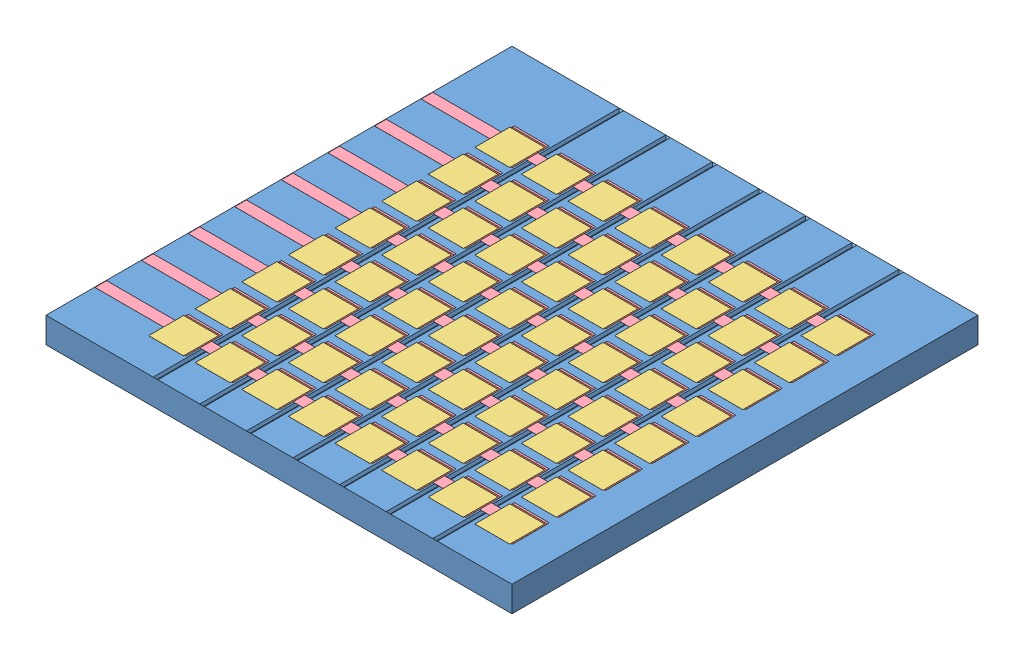
SolidWorks assembly Assem1, configuration Default. Lengths in mm.
Overall size (20 1.11 20).
6 component instances, 6 part files, 6 mates.
Components (placement in the parent):
- glass substrate-1: glass substrate [Default] at (-2.0419 7.7484 26.5448) size (20 1.1 20)
- pattern deposition layer(solid)-1: pattern deposition layer(solid) [Default] at (-2.0787 8.9033 26.5448) size (37.61 1.97 20.02) (hidden)
- PDOT PSS-3: PDOT PSS [Default] at (27.0437 8.8557 10.0564) size (15.5 0 15.5)
- Ruthenium red-1: Ruthenium red [Default] at (26.9855 8.8557 10.1147) size (15.5 0 15.5)
- Cathode pattern deposition layer-1: Cathode pattern deposition layer [Default] at (-2.0419 8.9033 26.5448) size (37.61 1.98 20.02) (hidden)
- Galinstan-1: Galinstan [Default] at (12.3174 8.8556 9.2101) size (18.5 0 15.5)
Mates (geometry in assembly coordinates):
- Tangent1: tangent: plane of glass substrate-1 through (-2.0419 8.8484 26.5448) normal (0 1 0); face of pattern deposition layer(solid)-1
- Coincident5: coincident aligned: plane of glass substrate-1 through (-2.0419 8.8484 26.5448) normal (0 0 1); plane of pattern deposition layer(solid)-1 through (-2.0787 8.9033 26.5448) normal (0 0 1)
- Tangent2: tangent: plane of glass substrate-1 through (-2.0419 8.8484 26.5448) normal (0 1 0); face of Cathode pattern deposition layer-1
- Coincident6: coincident aligned: plane of glass substrate-1 through (-2.0419 8.8484 26.5448) normal (0 0 1); plane of Cathode pattern deposition layer-1 through (-2.0419 8.9033 26.5448) normal (0 0 1)
- Coincident7: coincident aligned: line of glass substrate-1 through (-2.0419 8.8484 26.5448) axis (0 -1 0); line of Cathode pattern deposition layer-1 through (-2.0419 8.9129 26.5448) axis (0 -1 0)
- Lock1: lock: 
